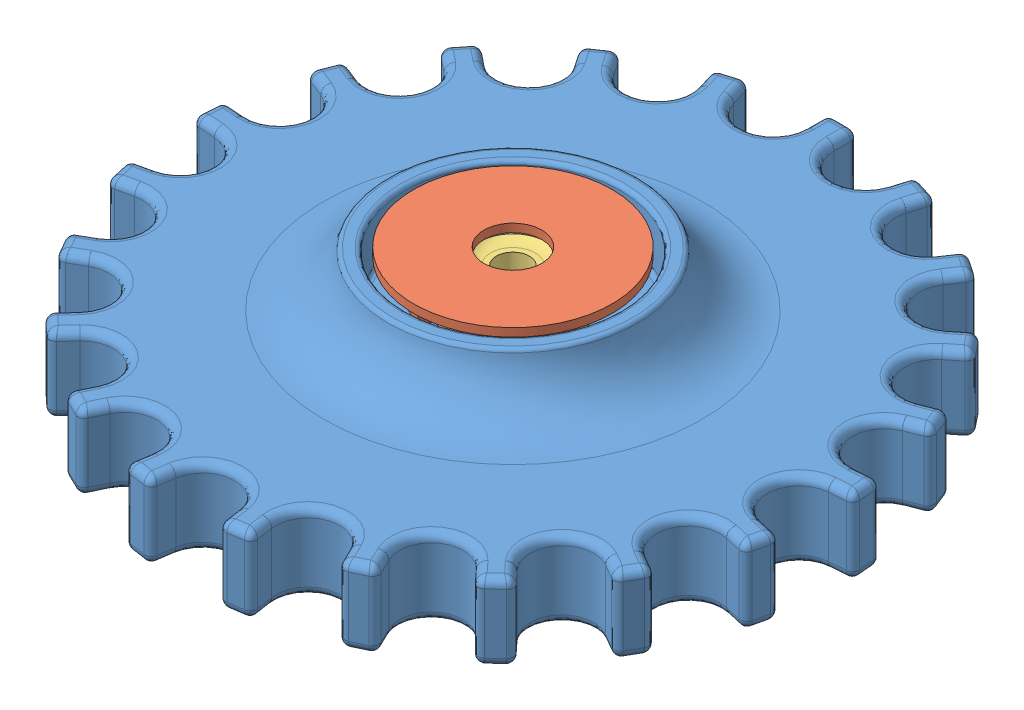
SolidWorks assembly Montagem Roda Mov. Encoder, configuration Default. Lengths in mm.
Overall size (79.81 15.92 79.59).
5 component instances, 5 part files, 10 mates.
Components (placement in the parent):
- Engrenagem Mov. Red. Encoder - 11,92_7988-1: Engrenagem Mov. Red. Encoder - 11,92_7988 [Valor predeterminado] at origin size (79.81 15.82 79.59)
- Encoder Motor Mod.-1: Encoder Motor Mod. [Valor predeterminado] at (0 10.795 0) x (-1 0 0) z (0 0 1) size (24 6 24)
- Imã Encoder Mod.-1: Imã Encoder Mod. [Valor predeterminado] at (0 8.065 0) x (-0.210312 0 -0.977634) z (0.977634 0 -0.210312) size (13.5 3.5 13.5)
- Arruela M4-1: Arruela M4 [Default] at (0 5.705 0) x (0.286538 0 -0.958069) z (0 -1 0) size (14.16 14.16 1.22)
- Fixador Encoder Direita-1: Fixador Encoder Direita [Default] at (0 12.895 0) x (-1 0 0) z (0 1 0) size (32.1 27.1 3.2) (hidden)
Mates (geometry in assembly coordinates):
- Concentric1: concentric aligned: cylinder of Engrenagem Mov. Red. Encoder - 11,92_7988-1 through (0 -4.625 0) axis (0 1 0) radius 2.55; cylinder of Imã Encoder Mod.-1 through (0 6.315 0) axis (0 1 0) radius 2
- Concentric2: concentric aligned: cylinder of Encoder Motor Mod.-1 through (0 10.295 0) axis (0 1 0) radius 3.5; cylinder of Imã Encoder Mod.-1 through (0 6.315 0) axis (0 1 0) radius 2
- Coincident2: coincident anti-aligned: plane of Encoder Motor Mod.-1 through (0 10.795 0) normal (-1 0 0)
- Distance1: distance = 0.2 mm anti-aligned: plane of Encoder Motor Mod.-1 through (0 5.295 0) normal (0 -1 0); plane of Engrenagem Mov. Red. Encoder - 11,92_7988-1 through (0 5.095 0) normal (0 1 0)
- Coincident3: coincident anti-aligned: plane of Imã Encoder Mod.-1 through (0 6.315 0) normal (0 -1 0); plane of Arruela M4-1 through (0 6.315 0) normal (0 1 0)
- Concentric3: concentric aligned: cylinder of Imã Encoder Mod.-1 through (0 6.315 0) axis (0 1 0) radius 2; cylinder of Arruela M4-1 through (0 5.095 0) axis (0 1 0) radius 2.15
- Coincident5: coincident anti-aligned: plane of Engrenagem Mov. Red. Encoder - 11,92_7988-1 through (0 5.095 0) normal (0 1 0); plane of Arruela M4-1 through (0 5.095 0) normal (0 -1 0)
- Concentric4: concentric aligned: circle of Encoder Motor Mod.-1; cylinder of Fixador Encoder Direita-1 through (0 14.495 0) axis (0 -1 0) radius 4.5
- Coincident6: coincident anti-aligned: plane of Encoder Motor Mod.-1 through (0 11.295 0) normal (0 1 0); plane of Fixador Encoder Direita-1 through (0 11.295 0) normal (0 -1 0)
- Coincident7: coincident aligned: plane of Fixador Encoder Direita-1 through (0 12.895 0) normal (0 0 1)
